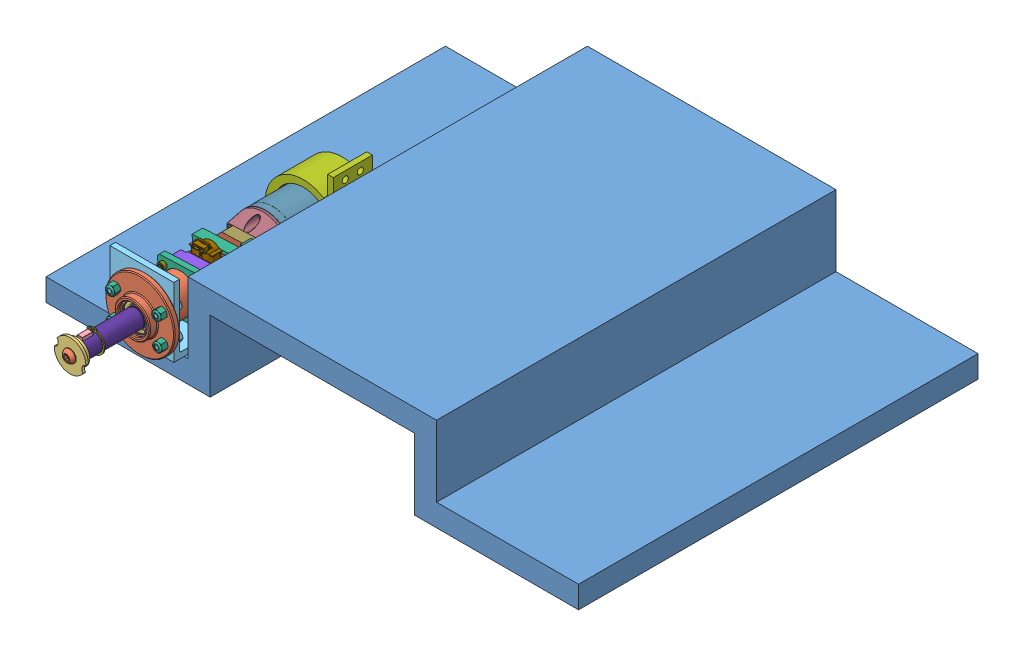
SolidWorks assembly assemblage moteur et sol, configuration Default. Lengths in mm.
Overall size (600 122.56 583.01).
45 component instances, 25 part files, 2 mates.
Components (placement in the parent):
- Plancher-1: Plancher [Default] at (24.4281 410.0978 499.9535) size (600 105 450)
- PB2023-M054 DRIVETRAIN ASSEMBLY-v1-1: PB2023-M054 DRIVETRAIN ASSEMBLY-v1 [Default] at (199.7495 469.8444 927.781) x (-0.033355 0.999444 -0.000105) z (0 0.000105 1) size (108.26 108.55 344.65)
  - A12220103_FRONT_BRACKET_ASSEMBLY-1: A12220103_FRONT_BRACKET_ASSEMBLY [Default] at origin size (78 78 534.65)
    - A12220101_FRONT_CASE_ASSEMBLY-1: A12220101_FRONT_CASE_ASSEMBLY [Default] at origin size (78 78 141.2)
      - 12220103_FRONT_HOUSING-1: 12220103_FRONT_HOUSING [Default] at (-52 141.0744 -192.9876) x (0 0 -1) z (1 0 0) size (60 78 78)
      - BALL BEARING-1: BALL BEARING [6656K203] at origin size (32 32 10)
      - BALL BEARING-2: BALL BEARING [6656K203] at (0 0 41) size (32 32 10)
      - Internal Retaining Ring (98455A129)-1: Internal Retaining Ring (98455A129) [98455A129] at (0.0361 0.7992 46) x (0.998982 -0.045107 0) z (0 0 1) size (34.4 33.81 1.2)
    - M6 x 20mm Steel Hex Head Screw (91310A333)-2: M6 x 20mm Steel Hex Head Screw (91310A333) [91310A333] at (-15.125 -26.1973 37.15) x (0 0 1) z (-0.44141 0.897306 0) size (24.4 11.55 10)
    - M6 x 1mm Steel Hex LockNut (90592A016)-1: M6 x 1mm Steel Hex LockNut (90592A016) [97260A101] at (15.125 -26.1973 41.85) x (0.928554 -0.371196 0) z (-0.371196 -0.928554 0) size (10 8.38 11.55)
    - 20MM External Retaining Ring (98541A123)-4: 20MM External Retaining Ring (98541A123) [98541A123] at (0 0 92.94) x (0 0 1) z (-0.186581 0.98244 0) size (1.2 25.1 22.76)
    - A12220110_FRONT_SHAFT_ASSEMBLY-1: A12220110_FRONT_SHAFT_ASSEMBLY [Default] at (1.7896 0 -19.01) x (0 -1 0) z (0 0 1) size (64.01 67.32 307.03)
      - A12220105_MOTOR_BRACKET_ASSEMBLY-1: A12220105_MOTOR_BRACKET_ASSEMBLY [Default] at origin size (64.01 67.32 280.24) (flexible)
        - 12220106-051 MiniCIM Motor Assembly-1: 12220106-051 MiniCIM Motor Assembly [Default] at origin size (64.01 67.32 218.97)
          - Gearbox Assembly-1: Gearbox Assembly [Default] at (34.0244 -12.4567 -92.7758) x (0 0 1) z (-1 0 0) size (123.35 56.32 44.45)
            - Output Housing-2: Output Housing [Default] at (64.8023 -0.856 18.2213) x (1 0 0) z (0 -1 0) size (75.7 44.45 56.32)
              - Housing-1: Housing [Default] at (19.8785 -6.4219 -11.5232) size (18.13 44.45 42)
              - Encoder.step-1: Encoder.step [Default] at (12.6785 15.8031 -11.5232) x (0 0 1) z (-1 0 0) size (56.32 42 21.21)
              - Gearbox_output_shaft-1: Gearbox_output_shaft [Default] at origin size (63.51 17 17)
            - Ring Gears-1: Ring Gears [Default] at (71.9808 10.6671 11.7994) x (1 0 0) z (0 -1 0) size (32.2 42 42)
            - Ring Gear Stage 3-1: Ring Gear Stage 3 [Default] at (59.2808 10.6671 11.7994) x (1 0 0) z (0 -1 0) size (28.65 42 42)
          - CIM Adaptor.step-1: CIM Adaptor.step [Default] at (0 -1.7896 -68.72) x (0 -1 0) z (-1 0 0) size (64.01 21.63 64.01)
          - Mini CIM-1: Mini CIM [Default] at (0 -1.7896 -80.245) x (0 0 -1) z (1 0 0) size (101.22 64.01 64.01)
          - 8-32 X 3IN LG - Black-Oxide Alloy Steel Socket Head Screw (90044A516)-1: 8-32 X 3IN LG - Black-Oxide Alloy Steel Socket Head Screw (90044A516) [90044A516] at (17.5 15.7104 -75.245) x (-0.08536 0.99635 0) z (0 0 -1) size (6.86 6.86 81.33)
          - 8-32 X 3IN LG - Black-Oxide Alloy Steel Socket Head Screw (90044A516)-3: 8-32 X 3IN LG - Black-Oxide Alloy Steel Socket Head Screw (90044A516) [90044A516] at (-17.5 -19.2896 -75.245) x (-0.242255 0.970213 0) z (0 0 -1) size (6.86 6.86 81.33)
        - 10-32 X 0.875IN LG - Black-Oxide Alloy Steel Socket Head Screw (91251A346)-1: 10-32 X 0.875IN LG - Black-Oxide Alloy Steel Socket Head Screw (91251A346) [91251A346] at (-17.9605 16.1709 6.1805) x (0.130335 0.99147 0) z (0 0 1) size (7.94 7.94 27.67)
        - 10-32 X 0.875IN LG - Black-Oxide Alloy Steel Socket Head Screw (91251A346)-2: 10-32 X 0.875IN LG - Black-Oxide Alloy Steel Socket Head Screw (91251A346) [91251A346] at (17.9605 -19.7501 6.1805) x (0.872398 0.488796 0) z (0 0 1) size (7.94 7.94 27.67)
      - PB2023-M005 ROTARY SHAFT-1: PB2023-M005 ROTARY SHAFT [Default] at (0 -1.7896 136.57) x (0 0 -1) z (1 0 0) size (126.56 25 25)
      - 12220110_MOTOR_KEY-1: 12220110_MOTOR_KEY [Default] at (0 5.1764 16.3975) size (3.17 4.76 26.16)
    - M6 x 20mm Steel Hex Head Screw (91310A333)-7: M6 x 20mm Steel Hex Head Screw (91310A333) [91310A333] at (15.125 -26.1973 37.15) x (0 0 1) z (0.78025 0.625468 0) size (24.4 11.55 10)
    - M6 x 20mm Steel Hex Head Screw (91310A333)-9: M6 x 20mm Steel Hex Head Screw (91310A333) [91310A333] at (15.125 26.1973 37.15) x (0 0 1) z (0.877007 0.480477 0) size (24.4 11.55 10)
    - M6 x 20mm Steel Hex Head Screw (91310A333)-11: M6 x 20mm Steel Hex Head Screw (91310A333) [91310A333] at (-15.0958 26.1466 37.15) x (0 0 1) z (0.947118 0.320887 0) size (24.4 11.55 10)
    - M6 x 1mm Steel Hex LockNut (90592A016)-7: M6 x 1mm Steel Hex LockNut (90592A016) [97260A101] at (-15.125 -26.1973 41.85) x (0.975663 -0.219276 0) z (-0.219276 -0.975663 0) size (10 8.38 11.55)
    - M6 x 1mm Steel Hex LockNut (90592A016)-9: M6 x 1mm Steel Hex LockNut (90592A016) [97260A101] at (-15.125 26.1973 41.85) x (0.995642 -0.093258 0) z (-0.093258 -0.995642 0) size (10 8.38 11.55)
    - M6 x 1mm Steel Hex LockNut (90592A016)-11: M6 x 1mm Steel Hex LockNut (90592A016) [97260A101] at (15.2049 26.151 41.85) x (1 -0.000046 0) z (-0.000046 -1 0) size (10 8.38 11.55)
  - M6 x 25mm Steel Socket Head Screw (91290A330)-1: M6 x 25mm Steel Socket Head Screw (91290A330) [91290A330] at (-31.155 30 -64.48) x (0 -0.901175 -0.433456) z (1 0 0) size (10 10 31.46)
  - M6 x 25mm Steel Socket Head Screw (91290A330)-2: M6 x 25mm Steel Socket Head Screw (91290A330) [91290A330] at (-31.155 -30 -64.48) x (0 -0.15786 -0.987461) z (1 0 0) size (10 10 31.46)
  - M6 x 1mm Steel Hex LockNut (90592A016)-1: M6 x 1mm Steel Hex LockNut (90592A016) [97260A101] at (-33 -30 -64.48) x (0 0.608626 0.793457) z (0 -0.793457 0.608626) size (10 8.38 11.55)
  - M6 x 1mm Steel Hex LockNut (90592A016)-2: M6 x 1mm Steel Hex LockNut (90592A016) [97260A101] at (-33 30 -64.48) x (0 -0.994883 0.101031) z (0 -0.101031 -0.994883) size (10 8.38 11.55)
  - M8 X 20MM - 18-8 Stainless Steel Button Head Hex Drive Screws (97763A444)-1: M8 X 20MM - 18-8 Stainless Steel Button Head Hex Drive Screws (97763A444) [97763A444] at (0 0 124.825) x (0.999813 0.019347 0) z (0 0 1) size (14 14 25.15)
  - PB2023-M006 WHEEL END CAP CUSTOM WASHER-1: PB2023-M006 WHEEL END CAP CUSTOM WASHER [Default] at (0 0 117.56) x (0 0 -1) z (-0.345262 -0.938506 0) size (8.5 35.5 34.05)
  - 98870A743_Machine Key-1: 98870A743_Machine Key [98870A743] at (10 0 103.06) size (6 6 12)
  - braquette bleu-1: braquette bleu [Default] at (-31.6695 41.0614 35.5) x (0 0 -1) z (-0.032817 -0.999461 0) size (167 78 72)
  - braquette gearbox-3: braquette gearbox [Default] at (-21.822 24.8587 -4.13) x (0 0 -1) z (-0.999979 -0.006497 0) size (72.34 80.66 66.5)
  - braquette moteur- v2-1: braquette moteur- v2 [Default] at (-0.0001 -0.0033 -186.4208) x (0.033355 0.999444 0) z (0 0 -1) size (99.43 90.98 44)
Mates (geometry in assembly coordinates):
- Parallel4: parallel: plane of Plancher-1 through (74.4281 435.0978 949.9535) normal (0 1 0); plane of PB2023-M054 DRIVETRAIN ASSEMBLY-v1-1/braquette bleu-1 through (239.7673 436.8697 963.2844) normal (0.000538 -1 0.000105)
- Parallel5: parallel: plane of Plancher-1 through (234.4281 435.0978 949.9535) normal (-1 0 0); plane of PB2023-M054 DRIVETRAIN ASSEMBLY-v1-1/braquette moteur- v2-1 through (233.5467 493.6892 785.3577) normal (1 0 0)
